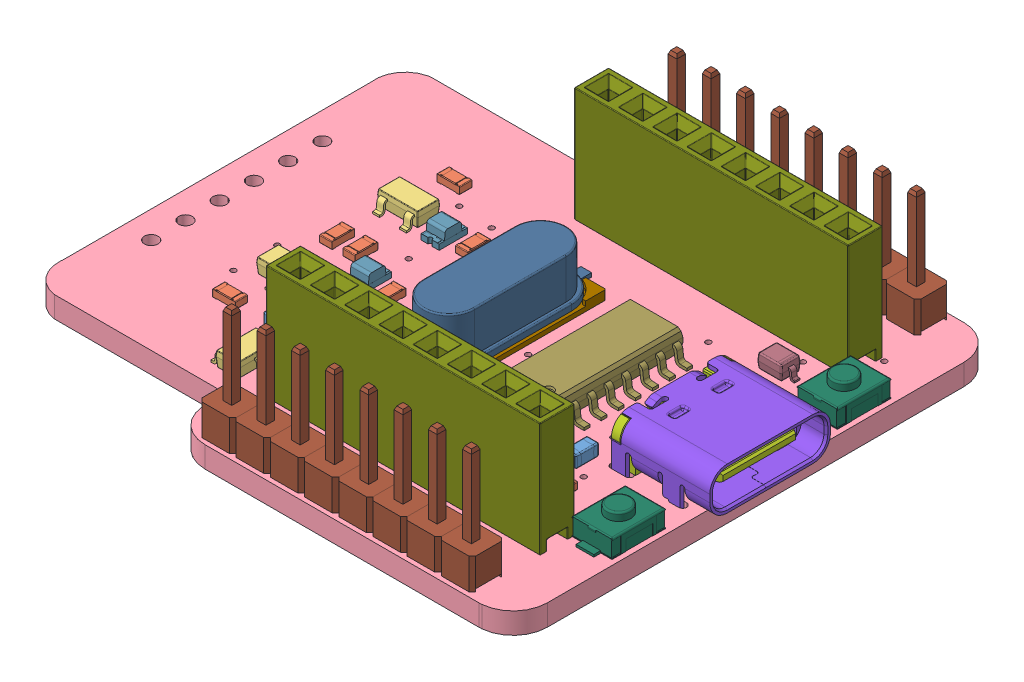
SolidWorks assembly ESP32-Cam Programmer v2, configuration Default. Lengths in mm.
Overall size (40.94 11.41 36).
58 component instances, 16 part files, 0 mates.
Components (placement in the parent):
- ESP32-Cam Programmer v2.step-1: ESP32-Cam Programmer v2.step [Default] at origin size (40.94 11.41 36)
  - ESP32Cam-Programmer-Public.step-1: ESP32Cam-Programmer-Public.step [Default] x (-1 0 0) z (0 1 0) size (40.02 36 2.78)
    - Packages.step-1: Packages.step [Default] at origin size (25.95 21.15 1.21)
      - C0603.step-1: C0603.step [Default] at (23.4825 13.564 1.57) x (0 1 0) z (0 0 1) size (1.7 0.9 0.9)
      - C0603.step-2: C0603.step [Default] at (23.5075 22.249 1.57) x (0 -1 0) z (0 0 1) size (1.7 0.9 0.9)
      - C0603.step-3: C0603.step [Default] at (9.83 24.574 1.57) x (0 1 0) z (0 0 1) size (1.7 0.9 0.9)
      - C0603.step-4: C0603.step [Default] at (7.9375 22.9865 1.57) x (0 -1 0) z (0 0 1) size (1.7 0.9 0.9)
      - C0603.step-5: C0603.step [Default] at (15.5575 24.574 1.57) x (0 -1 0) z (0 0 1) size (1.7 0.9 0.9)
      - C0603.step-6: C0603.step [Default] at (27.5 25.75 1.57) size (1.7 0.9 0.9)
      - R0603.step-1: R0603.step [Default] at (29.402 17.936 1.57) x (0 1 0) z (0 0 1) size (1.7 0.9 0.55)
      - R0603.step-2: R0603.step [Default] at (31.118 17.936 1.57) x (0 -1 0) z (0 0 1) size (1.7 0.9 0.55)
      - R0603.step-3: R0603.step [Default] at (31.233 25.776 1.57) size (1.7 0.9 0.55)
      - R0603.step-4: R0603.step [Default] at (30.3064 10.059 1.57) size (1.7 0.9 0.55)
      - R0603.step-5: R0603.step [Default] at (25.4 19.8465 1.57) x (0 -1 0) z (0 0 1) size (1.7 0.9 0.55)
      - R0603.step-6: R0603.step [Default] at (25.4 13.564 1.57) x (0 1 0) z (0 0 1) size (1.7 0.9 0.55)
      - R0603.step-7: R0603.step [Default] at (6.9925 27.0265 1.57) x (-1 0 0) z (0 0 1) size (1.7 0.9 0.55)
      - R0603.step-8: R0603.step [Default] at (6.985 25.5265 1.57) x (-1 0 0) z (0 0 1) size (1.7 0.9 0.55)
      - R0603.step-9: R0603.step [Default] at (23.495 17.9065 1.57) x (0 1 0) z (0 0 1) size (1.7 0.9 0.55)
      - R0603.step-10: R0603.step [Default] at (26.535 23.379 1.57) size (1.7 0.9 0.55)
      - SOT-23.step-1: SOT-23.step [Default] at (30.326 22.405 1.57) size (3.03 2.84 1.19)
      - SOT-23.step-2: SOT-23.step [Default] at (30.21 13.543 1.57) x (-1 0 0) z (0 0 1) size (3.03 2.84 1.19)
      - SOT-23.step-3: SOT-23.step [Default] at (26.5 29.25 1.57) x (0 1 0) z (0 0 1) size (3.03 2.84 1.19)
    - Board.step-1: Board.step [Default] at origin size (40.02 36 1.57)
  - HRO_TYPE-C-31-M-12 v1.step-1: HRO_TYPE-C-31-M-12 v1.step [Default] at (0.9151 1.5761 22.324) x (0 0 -1) z (0 1 0) size (8.95 7.9 4.2)
    - HRO_TYPE-C-31-M-12.step-1: HRO_TYPE-C-31-M-12.step [Default] at origin size (8.95 7.9 4.2)
      - ConPins.step-1: ConPins.step [Default] at origin size (6 4.32 0.61)
      - PcbPins.step-1: PcbPins.step [Default] at origin size (6.9 0.99 0.3)
      - Mold.step-1: Mold.step [Default] at origin size (8.95 6.5 3.7)
      - Frame.step-1: Frame.step [Default] at origin size (8.95 7.3 4.2)
  - smdcrystal v1.step-1: smdcrystal v1.step [Default] at (-19.686 1.5549 17.6774) x (0 0 1) z (-1 0 0) size (13.58 3.85 4.8)
    - kalip.step-1: kalip.step [Default] at origin size (11.7 0.7 4.8)
    - kristal.step-1: kristal.step [Default] at (0 0.35 0) size (13.58 3.85 4.35)
  - 8x_Male_Pin_2.54_mm v1.step-1: 8x_Male_Pin_2.54_mm v1.step [Default] at (-8.8034 -3.6587 -9.9145) size (20.32 11.1 2.4)
    - 1_Male_Pin_2.54_mm.step-1: 1_Male_Pin_2.54_mm.step [Default] at (3.8763 2.2562 11.0637) size (2.54 11.1 2.4)
    - 1_Male_Pin_2.54_mm.step-2: 1_Male_Pin_2.54_mm.step [Default] at (1.3363 2.2562 11.0637) size (2.54 11.1 2.4)
    - 1_Male_Pin_2.54_mm.step-3: 1_Male_Pin_2.54_mm.step [Default] at (-1.2037 2.2562 11.0637) size (2.54 11.1 2.4)
    - 1_Male_Pin_2.54_mm.step-4: 1_Male_Pin_2.54_mm.step [Default] at (-3.7437 2.2562 11.0637) size (2.54 11.1 2.4)
    - 1_Male_Pin_2.54_mm.step-5: 1_Male_Pin_2.54_mm.step [Default] at (-6.2837 2.2562 11.0637) size (2.54 11.1 2.4)
    - 1_Male_Pin_2.54_mm.step-6: 1_Male_Pin_2.54_mm.step [Default] at (-8.8237 2.2562 11.0637) size (2.54 11.1 2.4)
    - 1_Male_Pin_2.54_mm.step-7: 1_Male_Pin_2.54_mm.step [Default] at (-11.3637 2.2562 11.0637) size (2.54 11.1 2.4)
    - 1_Male_Pin_2.54_mm.step-8: 1_Male_Pin_2.54_mm.step [Default] at (-13.9037 2.2562 11.0637) size (2.54 11.1 2.4)
  - 8x_Male_Pin_2.54_mm v1.step-2: 8x_Male_Pin_2.54_mm v1.step [Default] at (-8.8034 -3.6587 23.1055) size (20.32 11.1 2.4)
    - 1_Male_Pin_2.54_mm.step-1: 1_Male_Pin_2.54_mm.step [Default] at (3.8763 2.2562 11.0637) size (2.54 11.1 2.4)
    - 1_Male_Pin_2.54_mm.step-2: 1_Male_Pin_2.54_mm.step [Default] at (1.3363 2.2562 11.0637) size (2.54 11.1 2.4)
    - 1_Male_Pin_2.54_mm.step-3: 1_Male_Pin_2.54_mm.step [Default] at (-1.2037 2.2562 11.0637) size (2.54 11.1 2.4)
    - 1_Male_Pin_2.54_mm.step-4: 1_Male_Pin_2.54_mm.step [Default] at (-3.7437 2.2562 11.0637) size (2.54 11.1 2.4)
    - 1_Male_Pin_2.54_mm.step-5: 1_Male_Pin_2.54_mm.step [Default] at (-6.2837 2.2562 11.0637) size (2.54 11.1 2.4)
    - 1_Male_Pin_2.54_mm.step-6: 1_Male_Pin_2.54_mm.step [Default] at (-8.8237 2.2562 11.0637) size (2.54 11.1 2.4)
    - 1_Male_Pin_2.54_mm.step-7: 1_Male_Pin_2.54_mm.step [Default] at (-11.3637 2.2562 11.0637) size (2.54 11.1 2.4)
    - 1_Male_Pin_2.54_mm.step-8: 1_Male_Pin_2.54_mm.step [Default] at (-13.9037 2.2562 11.0637) size (2.54 11.1 2.4)
  - SOIC16-150-50 v1.step-1: SOIC16-150-50 v1.step [Default] at (-12.6946 1.5456 17.6501) x (-1 0 0) z (0 0 -1) size (6 1.91 9.98)
  - SOD323 v1.step-1: SOD323 v1.step [Default] at (-6.2933 1.5429 9.9836) x (1 0 0) z (0 1 0) size (2.7 1.45 1.15)
  - LED-0805H1.1 v1.step-1: LED-0805H1.1 v1.step [Default] at (-27.3309 1.5431 14.687) x (0 0 -1) z (0 1 0) size (2.1 1.35 1.1)
  - LED-0805H1.1 v1.step-2: LED-0805H1.1 v1.step [Default] at (-27.3309 1.5431 18.5288) x (0 0 1) z (0 1 0) size (2.1 1.35 1.1)
  - 3x4x2mm - 2 Pad v1.step-1: 3x4x2mm - 2 Pad v1.step [Default] at (-1.8685 1.558 9.5842) x (0 0 -1) z (0 1 0) size (5 3 1.93)
  - 3x4x2mm - 2 Pad v1.step-2: 3x4x2mm - 2 Pad v1.step [Default] at (-1.8685 1.558 26.303) x (0 0 -1) z (0 1 0) size (5 3 1.93)
  - Female header 8P v2.step-1: Female header 8P v2.step [Default] at (-18.5674 4.7335 6.5416) x (1 0 0) z (0 1 0) size (20.32 2.54 11.41)
  - Female header 8P v2.step-2: Female header 8P v2.step [Default] at (-18.5674 4.7335 29.4016) x (1 0 0) z (0 1 0) size (20.32 2.54 11.41)
